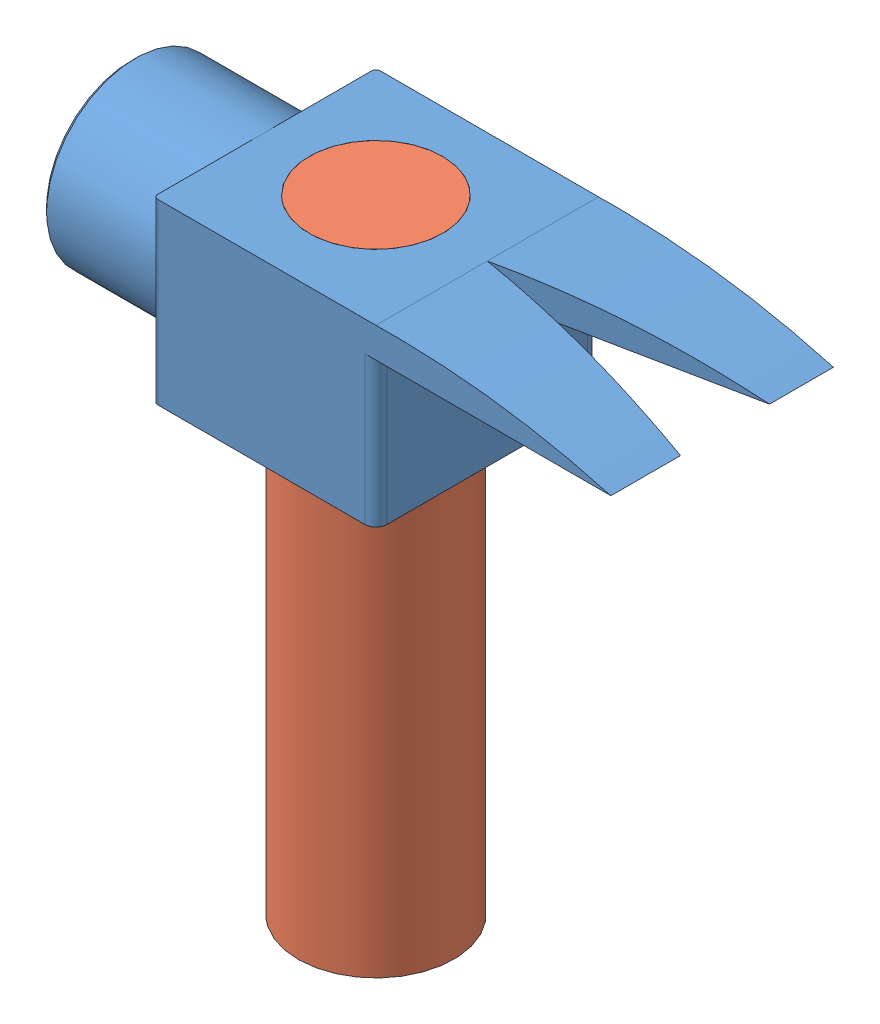
SolidWorks assembly Assem3, configuration Default. Lengths in mm.
Overall size (265.57 283.87 100.06).
2 component instances, 2 part files, 1 mates.
Components (placement in the parent):
- hammer 01-1: hammer 01 [Default] at (70.3308 141.1366 217.3111) size (265.57 83.87 100)
- hammer part 02-1: hammer part 02 [Default] at (119.5985 221.1366 266.5788) x (-0.645257 0 0.763966) z (0 -1 0) size (70 70 280)
Mates (geometry in assembly coordinates):
- Coincident1: coincident aligned: circle of hammer 01-1; circle of hammer part 02-1
